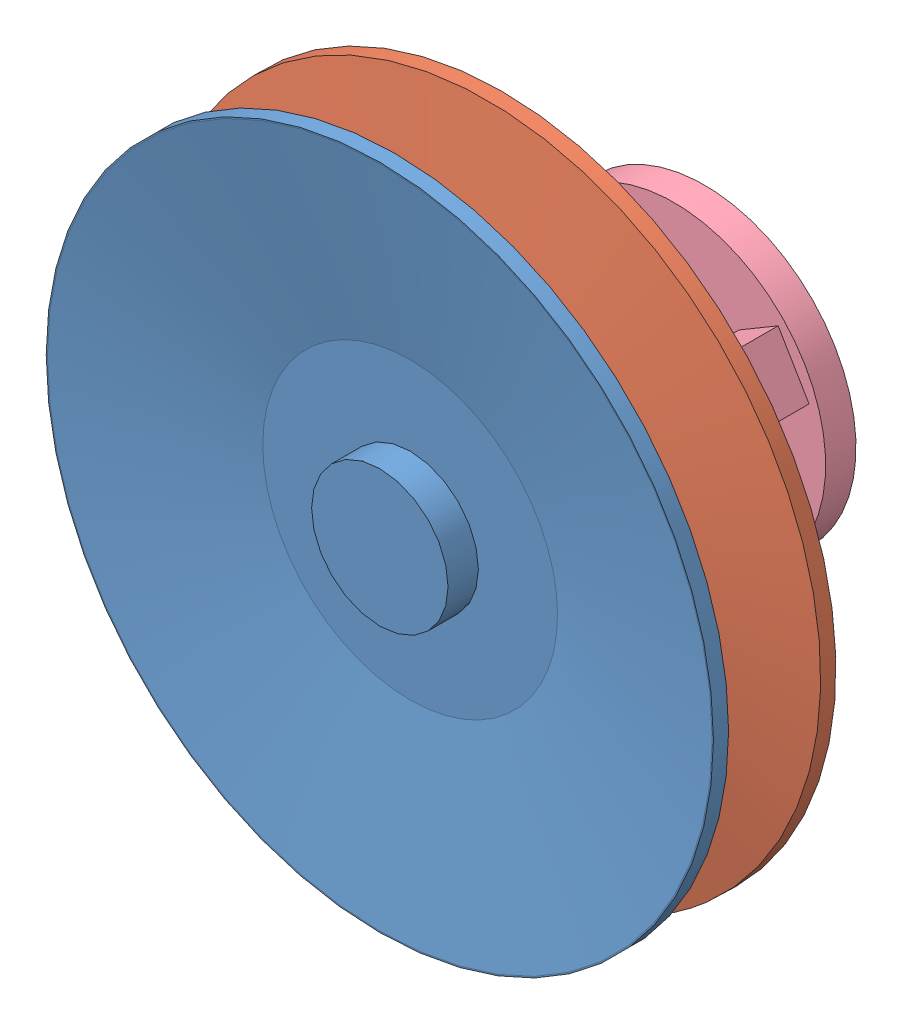
SolidWorks assembly Assembly secondary pulley, configuration Default. Lengths in mm.
Overall size (308.53 308.53 117).
5 component instances, 5 part files, 7 mates.
Components (placement in the parent):
- secondary fix pulley-1: secondary fix pulley [Default] at (-39.4938 3.563 -62.5803) size (220 220 117)
- secondary movable pulley-1: secondary movable pulley [Default] at (-39.4938 3.563 59.0309) x (0.609982 -0.792415 0) z (0 0 1) size (220 220 20)
- secondary spring-1: secondary spring [Default] at (-40.0038 1.6128 2.4197) x (0.989413 0.145124 0) z (0 0 1) size (63.97 64.96 59)
- weight-1: weight [Default] at (-39.4938 3.563 -7.5803) x (-0.509236 0.860627 0) z (0 0 1) size (100 100 54.68)
- ping-1: ping [Default] at (-39.4938 3.563 -17.5803) x (0.898075 0.439843 0) z (0 0 1) size (43.09 43.09 10)
Mates (geometry in assembly coordinates):
- Concentric1: concentric anti-aligned: cylinder of secondary fix pulley-1 through (-39.4938 3.563 99.4197) axis (0 0 -1) radius 22.5; cylinder of secondary movable pulley-1 through (-39.4938 3.563 31.0309) axis (0 0 1) radius 22.5
- Tangent4: tangent aligned: cylinder of secondary movable pulley-1 through (-39.4938 3.563 54.0309) axis (0 0 1) radius 32; face of secondary spring-1
- Concentric2: concentric anti-aligned: cylinder of secondary fix pulley-1 through (-39.4938 3.563 28.4197) axis (0 0 -1) radius 15; cylinder of weight-1 through (-39.4938 3.563 -7.5803) axis (0 0 1) radius 15
- Coincident5: coincident anti-aligned: plane of secondary spring-1 through (-40.0038 1.6128 2.4197) normal (0 0 -1); plane of weight-1 through (-39.4938 3.563 2.4197) normal (0 0 1)
- Concentric3: concentric aligned: circle of secondary fix pulley-1; cylinder of ping-1 through (-39.4938 3.563 -10.0803) axis (0 0 -1) radius 15
- Coincident7: coincident aligned: plane of secondary fix pulley-1 through (-39.4938 3.563 -17.5803) normal (0 0 -1); plane of ping-1 through (-39.4938 3.563 -17.5803) normal (0 0 -1)
- Coincident8: coincident anti-aligned: plane of weight-1 through (-39.4938 3.563 -7.5803) normal (0 0 -1); plane of ping-1 through (-39.4938 3.563 -7.5803) normal (0 0 1)
